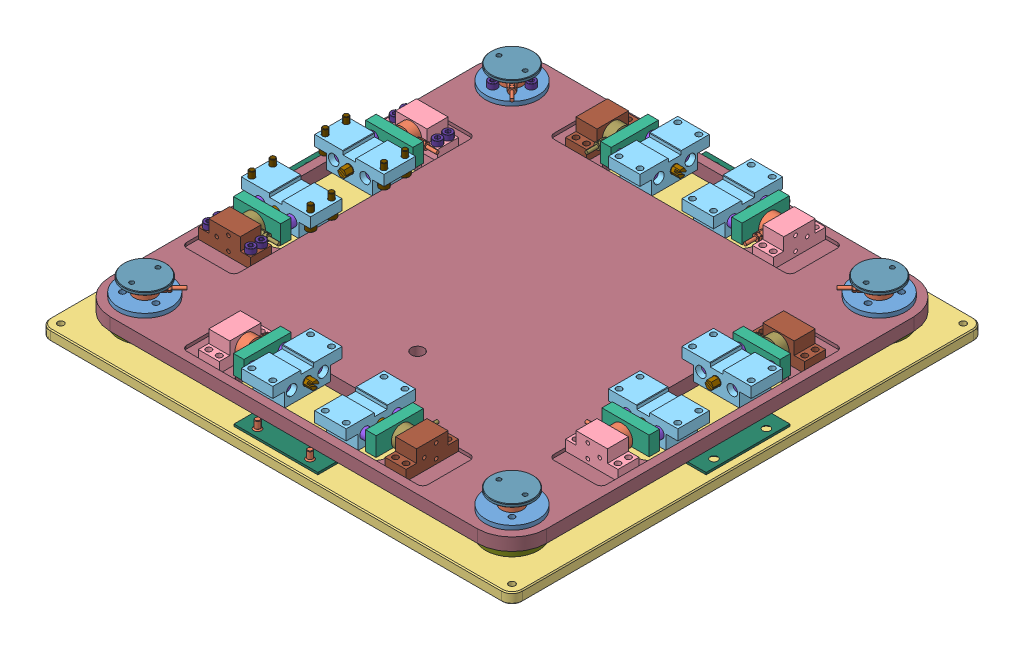
SolidWorks assembly Force_Plate_V5, configuration Default. Lengths in mm.
Overall size (450 58 450).
158 component instances, 22 part files, 0 mates.
Components (placement in the parent):
- loadcel_montaj-1-1: loadcel_montaj-1 [Default] at (175 -15.56 -175) x (0.258819 0 -0.965926) z (0.965926 0 0.258819) size (54.68 16 50)
  - loadcel_baglantý plakasý-1: loadcel_baglantý plakasý [Default] at origin size (50 5 50)
  - Mini_Loadcell-1: Mini_Loadcell [Default] at (0 4 0) x (0.866025 0 0.5) z (-0.5 0 0.866025) size (38.5 12 20)
  - socket head cap screw_iso(ISO 4762 M3 x 5 - 5N)-1: socket head cap screw_iso(ISO 4762 M3 x 5 - 5N) [Default] at (-6.4952 0.4 3.75) x (0 1 0) z (0.586788 0 -0.809741) size (8 5.5 5.5)
  - socket head cap screw_iso(ISO 4762 M3 x 5 - 5N)-2: socket head cap screw_iso(ISO 4762 M3 x 5 - 5N) [Default] at (0 0.4 -7.5) x (0 1 0) z (0.407862 0 0.913044) size (8 5.5 5.5)
  - socket head cap screw_iso(ISO 4762 M3 x 5 - 5N)-3: socket head cap screw_iso(ISO 4762 M3 x 5 - 5N) [Default] at (6.4952 0.4 3.75) x (0 1 0) z (-0.99465 0 -0.103303) size (8 5.5 5.5)
- loadcel_montaj-2-1: loadcel_montaj-2 [Default] at (175 -15.56 175) x (0.965926 0 0.258819) z (-0.258819 0 0.965926) size (54.68 16 50)
  - loadcel_baglantý plakasý-1: loadcel_baglantý plakasý [Default] at origin size (50 5 50)
  - Mini_Loadcell-1: Mini_Loadcell [Default] at (0 4 0) x (0.866025 0 0.5) z (-0.5 0 0.866025) size (38.5 12 20)
  - socket head cap screw_iso(ISO 4762 M3 x 5 - 5N)-1: socket head cap screw_iso(ISO 4762 M3 x 5 - 5N) [Default] at (6.4952 0.4 3.75) x (0 1 0) z (-0.99465 0 -0.103303) size (8 5.5 5.5)
  - socket head cap screw_iso(ISO 4762 M3 x 5 - 5N)-2: socket head cap screw_iso(ISO 4762 M3 x 5 - 5N) [Default] at (0 0.4 -7.5) x (0 1 0) z (0.407862 0 0.913044) size (8 5.5 5.5)
  - socket head cap screw_iso(ISO 4762 M3 x 5 - 5N)-3: socket head cap screw_iso(ISO 4762 M3 x 5 - 5N) [Default] at (-6.4952 0.4 3.75) x (0 1 0) z (0.586788 0 -0.809741) size (8 5.5 5.5)
- loadcel_montaj-3-1: loadcel_montaj-3 [Default] at (-175 -15.56 175) x (-0.258819 0 0.965926) z (-0.965926 0 -0.258819) size (54.68 16 50)
  - loadcel_baglantý plakasý-1: loadcel_baglantý plakasý [Default] at origin size (50 5 50)
  - Mini_Loadcell-1: Mini_Loadcell [Default] at (0 4 0) x (0.866025 0 0.5) z (-0.5 0 0.866025) size (38.5 12 20)
  - socket head cap screw_iso(ISO 4762 M3 x 5 - 5N)-1: socket head cap screw_iso(ISO 4762 M3 x 5 - 5N) [Default] at (6.4952 0.4 3.75) x (0 1 0) z (-0.99465 0 -0.103303) size (8 5.5 5.5)
  - socket head cap screw_iso(ISO 4762 M3 x 5 - 5N)-2: socket head cap screw_iso(ISO 4762 M3 x 5 - 5N) [Default] at (0 0.4 -7.5) x (0 1 0) z (0.407862 0 0.913044) size (8 5.5 5.5)
  - socket head cap screw_iso(ISO 4762 M3 x 5 - 5N)-3: socket head cap screw_iso(ISO 4762 M3 x 5 - 5N) [Default] at (-6.4952 0.4 3.75) x (0 1 0) z (0.586788 0 -0.809741) size (8 5.5 5.5)
- loadcel_montaj-4-1: loadcel_montaj-4 [Default] at (-175 -15.56 -175) x (-0.965926 0 -0.258819) z (0.258819 0 -0.965926) size (54.68 16 50)
  - loadcel_baglantý plakasý-1: loadcel_baglantý plakasý [Default] at origin size (50 5 50)
  - Mini_Loadcell-1: Mini_Loadcell [Default] at (0 4 0) x (0.866025 0 0.5) z (-0.5 0 0.866025) size (38.5 12 20)
  - socket head cap screw_iso(ISO 4762 M3 x 5 - 5N)-1: socket head cap screw_iso(ISO 4762 M3 x 5 - 5N) [Default] at (6.4952 0.4 3.75) x (0 1 0) z (-0.99465 0 -0.103303) size (8 5.5 5.5)
  - socket head cap screw_iso(ISO 4762 M3 x 5 - 5N)-2: socket head cap screw_iso(ISO 4762 M3 x 5 - 5N) [Default] at (0 0.4 -7.5) x (0 1 0) z (0.407862 0 0.913044) size (8 5.5 5.5)
  - socket head cap screw_iso(ISO 4762 M3 x 5 - 5N)-3: socket head cap screw_iso(ISO 4762 M3 x 5 - 5N) [Default] at (-6.4952 0.4 3.75) x (0 1 0) z (0.586788 0 -0.809741) size (8 5.5 5.5)
- loadcel yatay montaj-1: loadcel yatay montaj [Default] at (-175 -17.56 -99) size (53.5 22 31)
  - Mini_Loadcell-1: Mini_Loadcell [Default] at (0 11 19) x (-1 0 0) z (0 1 0) size (38.5 12 20)
  - Loadcell yatay ayak-1: Loadcell yatay ayak [Default] at origin size (50 22 20)
- yan baský yeni montaj(Varsayýlan-_flexible1)-1: yan baský yeni montaj(Varsayýlan-_flexible1) [Default] at (-175 5.44 -35) x (0 0 1) z (1 0 0) size (55.1 23.5 66)
  - yan baský gövdesi-1: yan baský gövdesi [Default] at origin size (30 23.5 66)
  - yan baský plaka-1: yan baský plaka [Default] at (-33 11 0) x (0 0 -1) z (1 0 0) size (45 18 10)
  - yan baský sýnýrlayýcý-1: yan baský sýnýrlayýcý [Default] at (-23 16.75 0) x (0 0 -1) z (1 0 0) size (20 6.5 3)
  - taþlanmýþ mil cap 10-1: taþlanmýþ mil cap 10 [Default] at (-30 12 -15) x (0 -0.879683 -0.47556) z (1 0 0) size (10 10 40)
  - taþlanmýþ mil cap 10-2: taþlanmýþ mil cap 10 [Default] at (-30 12 15) x (0 0.749994 0.661445) z (1 0 0) size (10 10 40)
  - yan baský ayar cývatasý-1: yan baský ayar cývatasý [Default] at (22.1 12 0) x (0 0 1) z (-1 0 0) size (8.43 8.43 50)
  - ISO 7046-1 - M3 x 6 - Z - 6C-1: ISO 7046-1 - M3 x 6 - Z - 6C [Default] at (-20 16.75 -7) x (-1 0 0) z (0 -0.924225 -0.381849) size (6 5.5 5.5)
  - ISO 7046-1 - M3 x 6 - Z - 6C-2: ISO 7046-1 - M3 x 6 - Z - 6C [Default] at (-20 16.75 7) x (-1 0 0) z (0 -0.924225 -0.381849) size (6 5.5 5.5)
- Aynalamaloadcel yatay montaj-1: Aynalamaloadcel yatay montaj [Default] at (-175 -17.56 99) size (53.5 22 31)
  - AynalamaLoadcell yatay ayak-1: AynalamaLoadcell yatay ayak [Default] at origin size (50 22 20)
  - AynalamaMini_Loadcell-1: AynalamaMini_Loadcell [Default] at (0 11 -19) x (-1 0 0) z (0 -1 0) size (38.5 12 20)
- yan baský yeni montaj(Varsayýlan)-1: yan baský yeni montaj(Varsayýlan) [Default] at (-175 5.44 35) x (0 0 -1) z (-1 0 0) size (55.1 23.5 66)
  - yan baský gövdesi-1: yan baský gövdesi [Default] at origin size (30 23.5 66)
  - yan baský plaka-1: yan baský plaka [Default] at (-33 11 0) x (0 0 -1) z (1 0 0) size (45 18 10)
  - yan baský sýnýrlayýcý-1: yan baský sýnýrlayýcý [Default] at (-23 16.75 0) x (0 0 -1) z (1 0 0) size (20 6.5 3)
  - taþlanmýþ mil cap 10-1: taþlanmýþ mil cap 10 [Default] at (-30 12 -15) x (0 -0.879683 -0.47556) z (1 0 0) size (10 10 40)
  - taþlanmýþ mil cap 10-2: taþlanmýþ mil cap 10 [Default] at (-30 12 15) x (0 0.749994 0.661445) z (1 0 0) size (10 10 40)
  - yan baský ayar cývatasý-1: yan baský ayar cývatasý [Default] at (22.1 12 0) x (0 0 1) z (-1 0 0) size (8.43 8.43 50)
  - ISO 7046-1 - M3 x 6 - Z - 6C-1: ISO 7046-1 - M3 x 6 - Z - 6C [Default] at (-20 16.75 -7) x (-1 0 0) z (0 -0.924225 -0.381849) size (6 5.5 5.5)
  - ISO 7046-1 - M3 x 6 - Z - 6C-2: ISO 7046-1 - M3 x 6 - Z - 6C [Default] at (-20 16.75 7) x (-1 0 0) z (0 -0.924225 -0.381849) size (6 5.5 5.5)
- yan baský yeni montaj(Varsayýlan)-1-1: yan baský yeni montaj(Varsayýlan)-1 [Default] at (-35 5.44 -175) x (1 0 0) z (0 0 -1) size (55.1 23.5 66)
  - yan baský gövdesi-1: yan baský gövdesi [Default] at origin size (30 23.5 66)
  - yan baský plaka-1: yan baský plaka [Default] at (-33 11 0) x (0 0 -1) z (1 0 0) size (45 18 10)
  - yan baský sýnýrlayýcý-1: yan baský sýnýrlayýcý [Default] at (-23 16.75 0) x (0 0 -1) z (1 0 0) size (20 6.5 3)
  - taþlanmýþ mil cap 10-1: taþlanmýþ mil cap 10 [Default] at (-30 12 15) x (0 0.749994 0.661445) z (1 0 0) size (10 10 40)
  - taþlanmýþ mil cap 10-2: taþlanmýþ mil cap 10 [Default] at (-30 12 -15) x (0 -0.879683 -0.47556) z (1 0 0) size (10 10 40)
  - yan baský ayar cývatasý-1: yan baský ayar cývatasý [Default] at (22.1 12 0) x (0 0 1) z (-1 0 0) size (8.43 8.43 50)
  - ISO 7046-1 - M3 x 6 - Z - 6C-1: ISO 7046-1 - M3 x 6 - Z - 6C [Default] at (-20 16.75 7) x (-1 0 0) z (0 -0.924225 -0.381849) size (6 5.5 5.5)
  - ISO 7046-1 - M3 x 6 - Z - 6C-2: ISO 7046-1 - M3 x 6 - Z - 6C [Default] at (-20 16.75 -7) x (-1 0 0) z (0 -0.924225 -0.381849) size (6 5.5 5.5)
- yan baský yeni montaj(Varsayýlan)-2-1: yan baský yeni montaj(Varsayýlan)-2 [Default] at (175 5.44 -35) x (0 0 1) z (1 0 0) size (55.1 23.5 66)
  - yan baský gövdesi-1: yan baský gövdesi [Default] at origin size (30 23.5 66)
  - yan baský plaka-1: yan baský plaka [Default] at (-33 11 0) x (0 0 -1) z (1 0 0) size (45 18 10)
  - yan baský sýnýrlayýcý-1: yan baský sýnýrlayýcý [Default] at (-23 16.75 0) x (0 0 -1) z (1 0 0) size (20 6.5 3)
  - taþlanmýþ mil cap 10-1: taþlanmýþ mil cap 10 [Default] at (-30 12 -15) x (0 -0.879683 -0.47556) z (1 0 0) size (10 10 40)
  - taþlanmýþ mil cap 10-2: taþlanmýþ mil cap 10 [Default] at (-30 12 15) x (0 0.749994 0.661445) z (1 0 0) size (10 10 40)
  - yan baský ayar cývatasý-1: yan baský ayar cývatasý [Default] at (22.1 12 0) x (0 0 1) z (-1 0 0) size (8.43 8.43 50)
  - ISO 7046-1 - M3 x 6 - Z - 6C-1: ISO 7046-1 - M3 x 6 - Z - 6C [Default] at (-20 16.75 7) x (-1 0 0) z (0 -0.924225 -0.381849) size (6 5.5 5.5)
  - ISO 7046-1 - M3 x 6 - Z - 6C-2: ISO 7046-1 - M3 x 6 - Z - 6C [Default] at (-20 16.75 -7) x (-1 0 0) z (0 -0.924225 -0.381849) size (6 5.5 5.5)
- yan baský yeni montaj(Varsayýlan)-3-1: yan baský yeni montaj(Varsayýlan)-3 [Default] at (35 5.44 175) x (-1 0 0) z (0 0 1) size (55.1 23.5 66)
  - yan baský gövdesi-1: yan baský gövdesi [Default] at origin size (30 23.5 66)
  - yan baský plaka-1: yan baský plaka [Default] at (-33 11 0) x (0 0 -1) z (1 0 0) size (45 18 10)
  - yan baský sýnýrlayýcý-1: yan baský sýnýrlayýcý [Default] at (-23 16.75 0) x (0 0 -1) z (1 0 0) size (20 6.5 3)
  - taþlanmýþ mil cap 10-1: taþlanmýþ mil cap 10 [Default] at (-30 12 15) x (0 0.749994 0.661445) z (1 0 0) size (10 10 40)
  - taþlanmýþ mil cap 10-2: taþlanmýþ mil cap 10 [Default] at (-30 12 -15) x (0 -0.879683 -0.47556) z (1 0 0) size (10 10 40)
  - yan baský ayar cývatasý-1: yan baský ayar cývatasý [Default] at (22.1 12 0) x (0 0 1) z (-1 0 0) size (8.43 8.43 50)
  - ISO 7046-1 - M3 x 6 - Z - 6C-1: ISO 7046-1 - M3 x 6 - Z - 6C [Default] at (-20 16.75 7) x (-1 0 0) z (0 -0.924225 -0.381849) size (6 5.5 5.5)
  - ISO 7046-1 - M3 x 6 - Z - 6C-2: ISO 7046-1 - M3 x 6 - Z - 6C [Default] at (-20 16.75 -7) x (-1 0 0) z (0 -0.924225 -0.381849) size (6 5.5 5.5)
- Aynalamaloadcel yatay montaj-1-1: Aynalamaloadcel yatay montaj-1 [Default] at (-99 -17.56 -175) x (0 0 1) z (-1 0 0) size (53.5 22 31)
  - AynalamaLoadcell yatay ayak-1: AynalamaLoadcell yatay ayak [Default] at origin size (50 22 20)
  - AynalamaMini_Loadcell-1: AynalamaMini_Loadcell [Default] at (0 11 -19) x (-1 0 0) z (0 -1 0) size (38.5 12 20)
- Aynalamaloadcel yatay montaj-2-1: Aynalamaloadcel yatay montaj-2 [Default] at (175 -17.56 -99) x (-1 0 0) z (0 0 -1) size (53.5 22 31)
  - AynalamaLoadcell yatay ayak-1: AynalamaLoadcell yatay ayak [Default] at origin size (50 22 20)
  - AynalamaMini_Loadcell-1: AynalamaMini_Loadcell [Default] at (0 11 -19) x (-1 0 0) z (0 -1 0) size (38.5 12 20)
- Aynalamaloadcel yatay montaj-3-1: Aynalamaloadcel yatay montaj-3 [Default] at (99 -17.56 175) x (0 0 -1) z (1 0 0) size (53.5 22 31)
  - AynalamaLoadcell yatay ayak-1: AynalamaLoadcell yatay ayak [Default] at origin size (50 22 20)
  - AynalamaMini_Loadcell-1: AynalamaMini_Loadcell [Default] at (0 11 -19) x (-1 0 0) z (0 -1 0) size (38.5 12 20)
- yan baský yeni montaj(Varsayýlan-_flexible2)-1: yan baský yeni montaj(Varsayýlan-_flexible2) [Default] at (35 5.44 -175) x (-1 0 0) z (0 0 1) size (55.1 23.5 66)
  - yan baský gövdesi-1: yan baský gövdesi [Default] at origin size (30 23.5 66)
  - yan baský plaka-1: yan baský plaka [Default] at (-31.8343 11 0) x (0 0 -1) z (1 0 0) size (45 18 10)
  - yan baský sýnýrlayýcý-1: yan baský sýnýrlayýcý [Default] at (-21.8343 16.75 0) x (0 0 -1) z (1 0 0) size (20 6.5 3)
  - taþlanmýþ mil cap 10-1: taþlanmýþ mil cap 10 [Default] at (-28.8343 12 -15) x (0 -0.879683 -0.47556) z (1 0 0) size (10 10 40)
  - taþlanmýþ mil cap 10-2: taþlanmýþ mil cap 10 [Default] at (-28.8343 12 15) x (0 0.749994 0.661445) z (1 0 0) size (10 10 40)
  - yan baský ayar cývatasý-1: yan baský ayar cývatasý [Default] at (23.2657 12 0) x (0 0 1) z (-1 0 0) size (8.43 8.43 50)
  - ISO 7046-1 - M3 x 6 - Z - 6C-1: ISO 7046-1 - M3 x 6 - Z - 6C [Default] at (-18.8343 16.75 -7) x (-1 0 0) z (0 -0.924225 -0.381849) size (6 5.5 5.5)
  - ISO 7046-1 - M3 x 6 - Z - 6C-2: ISO 7046-1 - M3 x 6 - Z - 6C [Default] at (-18.8343 16.75 7) x (-1 0 0) z (0 -0.924225 -0.381849) size (6 5.5 5.5)
- yan baský yeni montaj(Varsayýlan-_flexible3)-1: yan baský yeni montaj(Varsayýlan-_flexible3) [Default] at (175 5.44 35) x (0 0 -1) z (-1 0 0) size (55.1 23.5 66)
  - yan baský gövdesi-1: yan baský gövdesi [Default] at origin size (30 23.5 66)
  - yan baský plaka-1: yan baský plaka [Default] at (-31.8343 11 0) x (0 0 -1) z (1 0 0) size (45 18 10)
  - yan baský sýnýrlayýcý-1: yan baský sýnýrlayýcý [Default] at (-21.8343 16.75 0) x (0 0 -1) z (1 0 0) size (20 6.5 3)
  - taþlanmýþ mil cap 10-1: taþlanmýþ mil cap 10 [Default] at (-28.8343 12 -15) x (0 -0.879683 -0.47556) z (1 0 0) size (10 10 40)
  - taþlanmýþ mil cap 10-2: taþlanmýþ mil cap 10 [Default] at (-28.8343 12 15) x (0 0.749994 0.661445) z (1 0 0) size (10 10 40)
  - yan baský ayar cývatasý-1: yan baský ayar cývatasý [Default] at (23.2657 12 0) x (0 0 1) z (-1 0 0) size (8.43 8.43 50)
  - ISO 7046-1 - M3 x 6 - Z - 6C-1: ISO 7046-1 - M3 x 6 - Z - 6C [Default] at (-18.8343 16.75 -7) x (-1 0 0) z (0 -0.924225 -0.381849) size (6 5.5 5.5)
  - ISO 7046-1 - M3 x 6 - Z - 6C-2: ISO 7046-1 - M3 x 6 - Z - 6C [Default] at (-18.8343 16.75 7) x (-1 0 0) z (0 -0.924225 -0.381849) size (6 5.5 5.5)
- yan baský yeni montaj(Varsayýlan-_flexible4)-1: yan baský yeni montaj(Varsayýlan-_flexible4) [Default] at (-35 5.44 175) x (1 0 0) z (0 0 -1) size (55.1 23.5 66)
  - yan baský gövdesi-1: yan baský gövdesi [Default] at origin size (30 23.5 66)
  - yan baský plaka-1: yan baský plaka [Default] at (-33 11 0) x (0 0 -1) z (1 0 0) size (45 18 10)
  - yan baský sýnýrlayýcý-1: yan baský sýnýrlayýcý [Default] at (-23 16.75 0) x (0 0 -1) z (1 0 0) size (20 6.5 3)
  - taþlanmýþ mil cap 10-1: taþlanmýþ mil cap 10 [Default] at (-30 12 15) x (0 0.749994 0.661445) z (1 0 0) size (10 10 40)
  - taþlanmýþ mil cap 10-2: taþlanmýþ mil cap 10 [Default] at (-30 12 -15) x (0 -0.879683 -0.47556) z (1 0 0) size (10 10 40)
  - yan baský ayar cývatasý-1: yan baský ayar cývatasý [Default] at (22.1 12 0) x (0 0 1) z (-1 0 0) size (8.43 8.43 50)
  - ISO 7046-1 - M3 x 6 - Z - 6C-1: ISO 7046-1 - M3 x 6 - Z - 6C [Default] at (-20 16.75 7) x (-1 0 0) z (0 -0.924225 -0.381849) size (6 5.5 5.5)
  - ISO 7046-1 - M3 x 6 - Z - 6C-2: ISO 7046-1 - M3 x 6 - Z - 6C [Default] at (-20 16.75 -7) x (-1 0 0) z (0 -0.924225 -0.381849) size (6 5.5 5.5)
- loadcel yatay montaj-1-1: loadcel yatay montaj-1 [Default] at (99 -17.56 -175) x (0 0 1) z (-1 0 0) size (53.5 22 31)
  - Mini_Loadcell-1: Mini_Loadcell [Default] at (0 11 19) x (-1 0 0) z (0 1 0) size (38.5 12 20)
  - Loadcell yatay ayak-1: Loadcell yatay ayak [Default] at origin size (50 22 20)
- loadcel yatay montaj-2-1: loadcel yatay montaj-2 [Default] at (175 -17.56 99) x (-1 0 0) z (0 0 -1) size (53.5 22 31)
  - Mini_Loadcell-1: Mini_Loadcell [Default] at (0 11 19) x (-1 0 0) z (0 1 0) size (38.5 12 20)
  - Loadcell yatay ayak-1: Loadcell yatay ayak [Default] at origin size (50 22 20)
- loadcel yatay montaj-3-1: loadcel yatay montaj-3 [Default] at (-99 -17.56 175) x (0 0 -1) z (1 0 0) size (53.5 22 31)
  - Mini_Loadcell-1: Mini_Loadcell [Default] at (0 11 19) x (-1 0 0) z (0 1 0) size (38.5 12 20)
  - Loadcell yatay ayak-1: Loadcell yatay ayak [Default] at origin size (50 22 20)
- üst plaka-1: üst plaka [Default] at (0 -27.06 0) size (450 52.5 450) (hidden)
- alt plaka-1: alt plaka [Default] at (0 -34.56 0) size (416 12 416)
- taþlanmýþ plaka-1: taþlanmýþ plaka [Default] at (-175 0.44 -175) size (40 3 40)
- taþlanmýþ plaka-2: taþlanmýþ plaka [Default] at (-175 0.44 175) x (0 0 -1) z (1 0 0) size (40 3 40)
- taþlanmýþ plaka-3: taþlanmýþ plaka [Default] at (175 0.44 175) x (-1 0 0) z (0 0 -1) size (40 3 40)
- taþlanmýþ plaka-4: taþlanmýþ plaka [Default] at (175 0.44 -175) x (0 0 1) z (-1 0 0) size (40 3 40)
- Alt Týrnak-1: Alt Týrnak [Default] at (-225 -29.06 -40) x (0 0 1) z (-1 0 0) size (80 2 20)
- Alt Týrnak-2: Alt Týrnak [Default] at (225 -29.06 40) x (0 0 -1) z (1 0 0) size (80 2 20)
- Alt Týrnak-3: Alt Týrnak [Default] at (-40 -29.06 225) size (80 2 20)
- Alt Týrnak-4: Alt Týrnak [Default] at (40 -29.06 -225) x (-1 0 0) z (0 0 -1) size (80 2 20)
- ayak-1: ayak [Default] at (175 -36.56 175) x (-0.707107 0 0.707107) z (-0.707107 0 -0.707107) size (50 10 50)
- ayak-2: ayak [Default] at (-175 -36.56 -175) x (0.707107 0 -0.707107) z (0.707107 0 0.707107) size (50 10 50)
- ayak-3: ayak [Default] at (175 -36.56 -175) x (0.707107 0 0.707107) z (-0.707107 0 0.707107) size (50 10 50)
- ayak-4: ayak [Default] at (-175 -36.56 175) x (-0.707107 0 -0.707107) z (0.707107 0 -0.707107) size (50 10 50)
- socket head cap screw_iso(ISO 4762 M5 x 20 - 20C)-1: socket head cap screw_iso(ISO 4762 M5 x 20 - 20C) [Default] at (-195 -2.56 84) x (0 -1 0) z (0.66148 0 0.749963) size (25 8.5 8.5)
- socket head cap screw_iso(ISO 4762 M5 x 20 - 20C)-2: socket head cap screw_iso(ISO 4762 M5 x 20 - 20C) [Default] at (-155 -2.56 -84) x (0 -1 0) z (-0.66148 0 0.749963) size (25 8.5 8.5)
- socket head cap screw_iso(ISO 4762 M5 x 20 - 20C)-3: socket head cap screw_iso(ISO 4762 M5 x 20 - 20C) [Default] at (-155 -2.56 94) x (0 -1 0) z (0.66148 0 0.749963) size (25 8.5 8.5)
- socket head cap screw_iso(ISO 4762 M5 x 20 - 20C)-4: socket head cap screw_iso(ISO 4762 M5 x 20 - 20C) [Default] at (-195 -2.56 -84) x (0 -1 0) z (-0.66148 0 0.749963) size (25 8.5 8.5)
- socket head cap screw_iso(ISO 4762 M5 x 20 - 20C)-5: socket head cap screw_iso(ISO 4762 M5 x 20 - 20C) [Default] at (-195 -2.56 94) x (0 -1 0) z (0.66148 0 0.749963) size (25 8.5 8.5)
- socket head cap screw_iso(ISO 4762 M5 x 20 - 20C)-6: socket head cap screw_iso(ISO 4762 M5 x 20 - 20C) [Default] at (-160.5111 -5.56 -178.8823) x (0 -1 0) z (-0.931339 0 0.364153) size (25 8.5 8.5)
- socket head cap screw_iso(ISO 4762 M5 x 20 - 20C)-7: socket head cap screw_iso(ISO 4762 M5 x 20 - 20C) [Default] at (-155 -2.56 84) x (0 -1 0) z (0.66148 0 0.749963) size (25 8.5 8.5)
- socket head cap screw_iso(ISO 4762 M5 x 20 - 20C)-8: socket head cap screw_iso(ISO 4762 M5 x 20 - 20C) [Default] at (-185.6066 -5.56 -185.6066) x (0 -1 0) z (0.781035 0 0.624487) size (25 8.5 8.5)
- socket head cap screw_iso(ISO 4762 M5 x 20 - 20C)-9: socket head cap screw_iso(ISO 4762 M5 x 20 - 20C) [Default] at (-155 -2.56 -94) x (0 -1 0) z (-0.66148 0 0.749963) size (25 8.5 8.5)
- socket head cap screw_iso(ISO 4762 M5 x 20 - 20C)-10: socket head cap screw_iso(ISO 4762 M5 x 20 - 20C) [Default] at (-195 -2.56 -94) x (0 -1 0) z (-0.66148 0 0.749963) size (25 8.5 8.5)
- socket head cap screw_iso(ISO 4762 M5 x 20 - 20C)-11: socket head cap screw_iso(ISO 4762 M5 x 20 - 20C) [Default] at (-178.8823 -5.56 -160.5111) x (0 -1 0) z (0.150304 0 -0.98864) size (25 8.5 8.5)
- socket head cap screw_iso(ISO 4762 M5 x 16 - 16C)-1: socket head cap screw_iso(ISO 4762 M5 x 16 - 16C) [Default] at (-203 -9.56 -25) x (0 1 0) z (-0.546944 0 0.837169) size (21 8.5 8.5)
- socket head cap screw_iso(ISO 4762 M5 x 16 - 16C)-2: socket head cap screw_iso(ISO 4762 M5 x 16 - 16C) [Default] at (-147 -9.56 45) x (0 1 0) z (0.546944 0 0.837169) size (21 8.5 8.5)
- socket head cap screw_iso(ISO 4762 M5 x 16 - 16C)-3: socket head cap screw_iso(ISO 4762 M5 x 16 - 16C) [Default] at (-147 -9.56 25) x (0 1 0) z (0.546944 0 0.837169) size (21 8.5 8.5)
- socket head cap screw_iso(ISO 4762 M5 x 16 - 16C)-4: socket head cap screw_iso(ISO 4762 M5 x 16 - 16C) [Default] at (-203 -9.56 25) x (0 1 0) z (0.546944 0 0.837169) size (21 8.5 8.5)
- socket head cap screw_iso(ISO 4762 M5 x 16 - 16C)-5: socket head cap screw_iso(ISO 4762 M5 x 16 - 16C) [Default] at (-203 -9.56 -45) x (0 1 0) z (-0.546944 0 0.837169) size (21 8.5 8.5)
- socket head cap screw_iso(ISO 4762 M5 x 16 - 16C)-6: socket head cap screw_iso(ISO 4762 M5 x 16 - 16C) [Default] at (-147 -9.56 -45) x (0 1 0) z (-0.546944 0 0.837169) size (21 8.5 8.5)
- socket head cap screw_iso(ISO 4762 M5 x 16 - 16C)-7: socket head cap screw_iso(ISO 4762 M5 x 16 - 16C) [Default] at (-147 -9.56 -25) x (0 1 0) z (-0.546944 0 0.837169) size (21 8.5 8.5)
- socket head cap screw_iso(ISO 4762 M5 x 16 - 16C)-8: socket head cap screw_iso(ISO 4762 M5 x 16 - 16C) [Default] at (-203 -9.56 45) x (0 1 0) z (0.546944 0 0.837169) size (21 8.5 8.5)
- socket set screw flat point_iso(ISO 4026 - M5 x 6-C)-1: socket set screw flat point_iso(ISO 4026 - M5 x 6-C) [Default] at (-190 -18.06 35) x (0 1 0) z (-0.546944 0 0.837169) size (6 5 5)
- socket set screw flat point_iso(ISO 4026 - M5 x 6-C)-2: socket set screw flat point_iso(ISO 4026 - M5 x 6-C) [Default] at (-160 -18.06 35) x (0 1 0) z (-0.546944 0 0.837169) size (6 5 5)
- socket countersunk head screw_iso(ISO 10642 - M5 x 10 - 10N)-1: socket countersunk head screw_iso(ISO 10642 - M5 x 10 - 10N) [Default] at (25 -29.06 217.5) x (0 1 0) z (-0.546944 0 0.837169) size (10 9.43 9.43)
- socket countersunk head screw_iso(ISO 10642 - M5 x 10 - 10N)-2: socket countersunk head screw_iso(ISO 10642 - M5 x 10 - 10N) [Default] at (-25 -29.06 217.5) x (0 1 0) z (-0.546944 0 -0.837169) size (10 9.43 9.43)
- Taban Plakasý-1: Taban Plakasý [Default] at (0 -36.56 0) x (-1 0 0) z (0 0 1) size (450 10 450)
